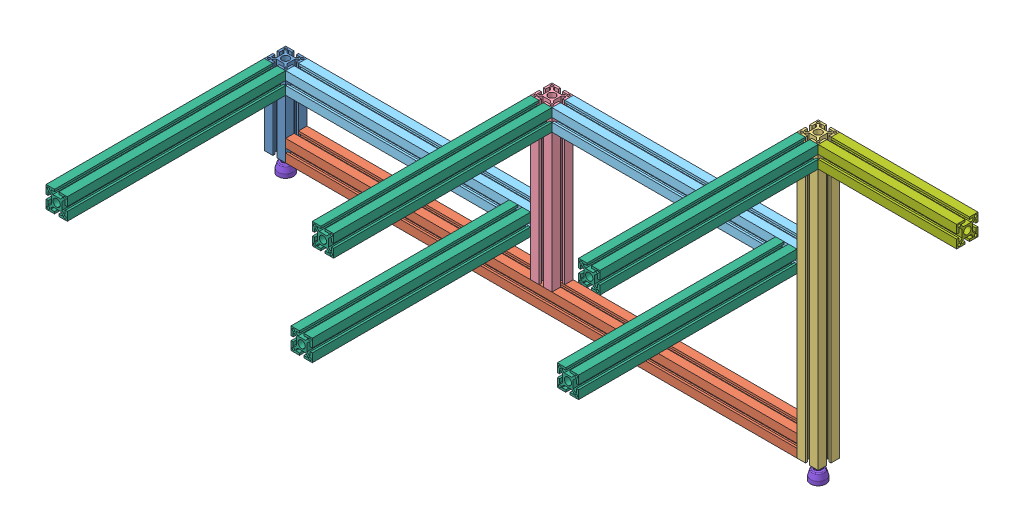
SolidWorks assembly Pd5 00-1-00, configuration Domyślna. Lengths in mm.
Overall size (1300 567 450).
14 component instances, 8 part files, 21 mates.
Components (placement in the parent):
- Profil 40x40x150-1: Profil 40x40x150 [Default] at (-10598.8427 2698.4912 6684.6061) x (0 0 -1) z (0 -1 0) size (40 40 150)
- Profil 40x40x960-1: Profil 40x40x960 [Default] at (-10558.8427 2548.4912 6684.6061) x (0 0 -1) z (1 0 0) size (40 40 960)
- Profil 40x40x530-1: Profil 40x40x530 [Default] at (-9558.8427 2548.4912 6684.6061) x (0 0 -1) z (0 1 0) size (40 40 530)
- Profil 40x40x300-1: Profil 40x40x300 [Default] at (-10098.8427 2888.4912 6684.6061) x (0 0 -1) z (0 -1 0) size (40 40 300)
- Profil 40x40x460-1: Profil 40x40x460 [Default] at (-10558.8427 2658.4912 6684.6061) x (0 0 -1) z (1 0 0) size (40 40 460)
- Profil 40x40x460-2: Profil 40x40x460 [Default] at (-10058.8427 2848.4912 6684.6061) x (0 0 -1) z (1 0 0) size (40 40 460)
- Profil 40x40x410-1: Profil 40x40x410 [Default] at (-10598.8427 2658.4912 6684.6061) size (40 40 410)
- Profil 40x40x410-2: Profil 40x40x410 [Default] at (-10138.8427 2658.4912 6684.6061) size (40 40 410)
- Profil 40x40x410-3: Profil 40x40x410 [Default] at (-10098.8427 2848.4912 6684.6061) size (40 40 410)
- Profil 40x40x410-4: Profil 40x40x410 [Default] at (-9598.8427 3038.4912 6684.6061) size (40 40 410)
- Profil 40x40x410-5: Profil 40x40x410 [Default] at (-9638.8427 2848.4912 6684.6061) size (40 40 410)
- Profil 40x40x260-1: Profil 40x40x260 [Default] at (-9298.8427 3038.4912 6644.6061) x (0 0 1) z (-1 0 0) size (40 40 260)
- b43-10-1: b43-10 [Domyślna] at (-10578.8427 2513.4912 6664.6061) x (0 0 -1) z (1 0 0) size (29 77 29)
- b43-10-2: b43-10 [Domyślna] at (-9578.8427 2513.4912 6664.6061) x (0 0 -1) z (1 0 0) size (29 77 29)
Mates (geometry in assembly coordinates):
- Wspólnie310: coincident: plane of Profil 40x40x150-1 through (-10558.8427 2699.4912 6644.6061) normal (0 0 -1); plane of Profil 40x40x960-1 through (-10559.8427 2564.4912 6644.6061) normal (0 0 -1)
- Wspólnie312: coincident: plane of Profil 40x40x150-1 through (-10558.8427 2699.4912 6660.6061) normal (1 0 0); plane of Profil 40x40x960-1 through (-10558.8427 2588.4912 6689.6061) normal (-1 0 0)
- Wspólnie320: coincident: plane of Profil 40x40x150-1 through (-10558.8427 2699.4912 6660.6061) normal (1 0 0); plane of Profil 40x40x460-1 through (-10558.8427 2698.4912 6689.6061) normal (-1 0 0)
- Wspólnie321: coincident: plane of Profil 40x40x150-1 through (-10558.8427 2699.4912 6644.6061) normal (0 0 -1); plane of Profil 40x40x460-1 through (-10559.8427 2674.4912 6644.6061) normal (0 0 -1)
- Wspólnie322: coincident: plane of Profil 40x40x150-1 through (-10558.8427 2698.4912 6689.6061) normal (0 1 0); plane of Profil 40x40x460-1 through (-10559.8427 2698.4912 6660.6061) normal (0 1 0)
- Wspólnie326: coincident: plane of Profil 40x40x150-1 through (-10598.8427 2699.4912 6668.6061) normal (-1 0 0); plane of Profil 40x40x410-1 through (-10598.8427 2682.4912 6683.6061) normal (-1 0 0)
- Wspólnie328: coincident: plane of Profil 40x40x150-1 through (-10574.8427 2699.4912 6684.6061) normal (0 0 1); plane of Profil 40x40x410-1 through (-10603.8427 2698.4912 6684.6061) normal (0 0 -1)
- Wspólnie314: coincident: plane of Profil 40x40x960-1 through (-10559.8427 2588.4912 6644.6061) normal (0 0 -1); plane of Profil 40x40x530-1 through (-9598.8427 2547.4912 6644.6061) normal (0 0 -1)
- Wspólnie315: coincident: plane of Profil 40x40x960-1 through (-10559.8427 2548.4912 6668.6061) normal (0 -1 0); plane of Profil 40x40x530-1 through (-9598.8427 2548.4912 6689.6061) normal (0 -1 0)
- Wspólnie316: coincident: plane of Profil 40x40x960-1 through (-10559.8427 2588.4912 6644.6061) normal (0 0 -1); plane of Profil 40x40x300-1 through (-10082.8427 2889.4912 6644.6061) normal (0 0 -1)
- Wspólnie318: coincident: plane of Profil 40x40x960-1 through (-10559.8427 2588.4912 6660.6061) normal (0 1 0); plane of Profil 40x40x300-1 through (-10098.8427 2588.4912 6684.6061) normal (0 -1 0)
- Wspólnie323: coincident: plane of Profil 40x40x300-1 through (-10058.8427 2889.4912 6684.6061) normal (1 0 0); plane of Profil 40x40x460-2 through (-10058.8427 2888.4912 6689.6061) normal (-1 0 0)
- Wspólnie324: coincident: plane of Profil 40x40x300-1 through (-10058.8427 2889.4912 6644.6061) normal (0 0 -1); plane of Profil 40x40x460-2 through (-10059.8427 2888.4912 6644.6061) normal (0 0 -1)
- Wspólnie325: coincident: plane of Profil 40x40x300-1 through (-10058.8427 2888.4912 6689.6061) normal (0 1 0); plane of Profil 40x40x460-2 through (-10059.8427 2888.4912 6660.6061) normal (0 1 0)
- Wspólnie327: coincident: plane of Profil 40x40x460-1 through (-10559.8427 2698.4912 6684.6061) normal (0 1 0); plane of Profil 40x40x410-1 through (-10598.8427 2698.4912 6683.6061) normal (0 1 0)
- Wspólnie351: coincident: plane of Profil 40x40x410-4 through (-9574.8427 3078.4912 6683.6061) normal (0 1 0); plane of Profil 40x40x260-1 through (-9297.8427 3078.4912 6644.6061) normal (0 1 0)
- Wspólnie352: coincident: plane of Profil 40x40x530-1 through (-9574.8427 2547.4912 6644.6061) normal (0 0 -1); plane of Profil 40x40x260-1 through (-9297.8427 3062.4912 6644.6061) normal (0 0 -1)
- Wspólnie353: coincident: plane of Profil 40x40x530-1 through (-9558.8427 2547.4912 6668.6061) normal (1 0 0); plane of Profil 40x40x260-1 through (-9558.8427 3038.4912 6644.6061) normal (-1 0 0)
- Koncentryczne2: concentric anti-aligned: cylinder of Profil 40x40x150-1 through (-10578.8427 2699.4912 6664.6061) axis (0 -1 0) radius 6.85; cylinder of b43-10-1 through (-10578.8427 2509.7412 6664.6061) axis (0 1 0) radius 5
- Koncentryczne1: concentric aligned: cylinder of Profil 40x40x530-1 through (-9578.8427 2547.4912 6664.6061) axis (0 1 0) radius 6.85; cylinder of b43-10-2 through (-9578.8427 2509.7412 6664.6061) axis (0 1 0) radius 5
- Wspólnie3: coincident aligned: plane of b43-10-1 through (-10578.8427 2511.4912 6664.6061) normal (0 -1 0); plane of b43-10-2 through (-9578.8427 2511.4912 6664.6061) normal (0 -1 0)
